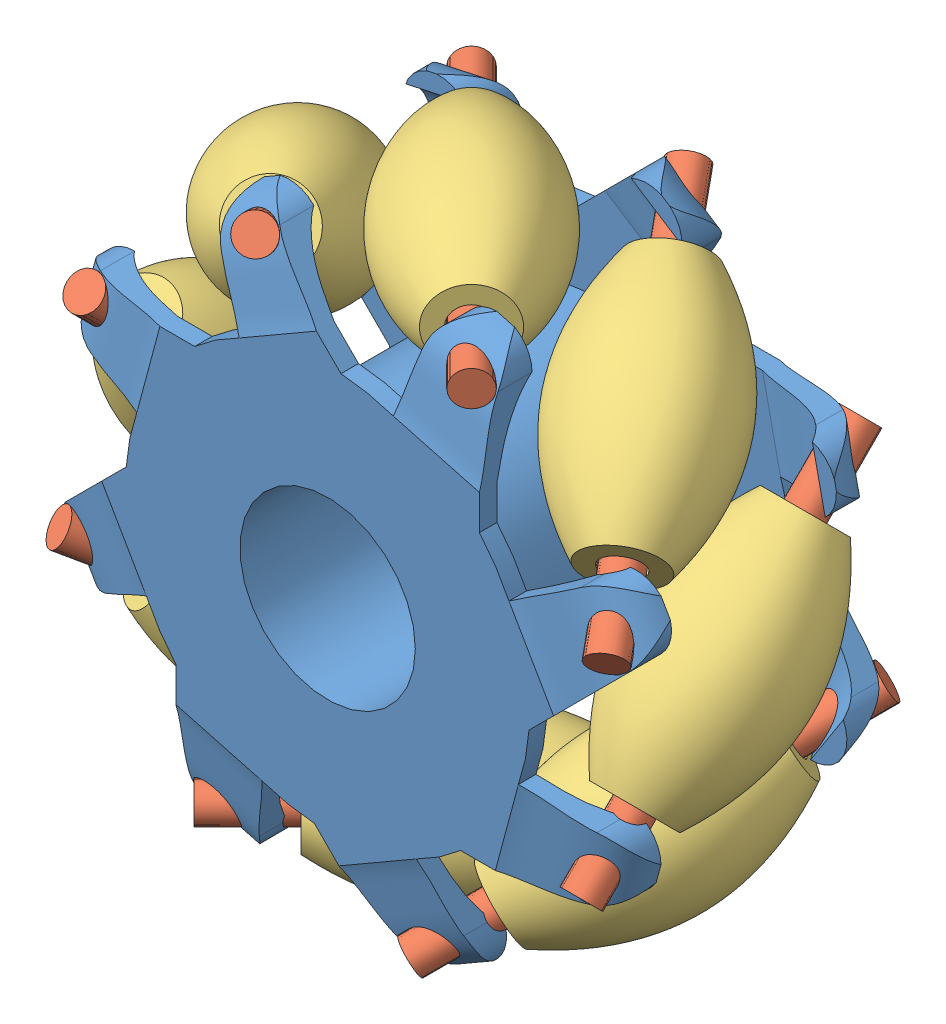
SolidWorks assembly Assem1, configuration Default. Lengths in mm.
Overall size (74.83 74.83 34.72).
17 component instances, 3 part files, 6 mates.
Components (placement in the parent):
- wheel_rim-1: wheel_rim [Default] at (28.8955 -22.2475 34.9813) size (66.41 66.41 33.64)
- wheel_rod-1: wheel_rod [Default] at (12.8892 6.0837 4.5688) x (0.707107 0 -0.707107) z (0.707107 0 0.707107) size (4 4 45)
- wheel_roller-1: wheel_roller [Default] at (28.9041 6.0837 20.5836) x (0 -1 0) z (-0.707107 0 0.707107) size (17.4 27.5 17.4)
- wheel_roller-9: wheel_roller [Default] at (8.8684 -2.2083 20.5836) x (0.707107 -0.707107 0) z (-0.5 -0.5 0.707107) size (17.4 27.5 17.4)
- wheel_roller-10: wheel_roller [Default] at (0.5643 -22.239 20.5836) x (1 0 0) z (0 -0.707107 0.707107) size (17.4 27.5 17.4)
- wheel_roller-11: wheel_roller [Default] at (8.8562 -42.2747 20.5836) x (0.707107 0.707107 0) z (0.5 -0.5 0.707107) size (17.4 27.5 17.4)
- wheel_roller-12: wheel_roller [Default] at (28.8869 -50.5788 20.5836) x (0 1 0) z (0.707107 0 0.707107) size (17.4 27.5 17.4)
- wheel_roller-13: wheel_roller [Default] at (48.9227 -42.2868 20.5836) x (-0.707107 0.707107 0) z (0.5 0.5 0.707107) size (17.4 27.5 17.4)
- wheel_roller-14: wheel_roller [Default] at (57.2268 -22.2561 20.5836) x (-1 0 0) z (0 0.707107 0.707107) size (17.4 27.5 17.4)
- wheel_roller-15: wheel_roller [Default] at (48.9348 -2.2204 20.5836) x (-0.707107 -0.707107 0) z (-0.5 0.5 0.707107) size (17.4 27.5 17.4)
- wheel_rod-9: wheel_rod [Default] at (-2.4558 -13.5325 4.5688) x (0.5 0.5 -0.707107) z (0.5 0.5 0.707107) size (4 4 45)
- wheel_rod-10: wheel_rod [Default] at (0.5643 -38.2538 4.5688) x (0 0.707107 -0.707107) z (0 0.707107 0.707107) size (4 4 45)
- wheel_rod-11: wheel_rod [Default] at (20.1805 -53.5989 4.5688) x (-0.5 0.5 -0.707107) z (-0.5 0.5 0.707107) size (4 4 45)
- wheel_rod-12: wheel_rod [Default] at (44.9018 -50.5788 4.5688) x (-0.707107 0 -0.707107) z (-0.707107 0 0.707107) size (4 4 45)
- wheel_rod-13: wheel_rod [Default] at (60.2469 -30.9626 4.5688) x (-0.5 -0.5 -0.707107) z (-0.5 -0.5 0.707107) size (4 4 45)
- wheel_rod-14: wheel_rod [Default] at (57.2268 -6.2413 4.5688) x (0 -0.707107 -0.707107) z (0 -0.707107 0.707107) size (4 4 45)
- wheel_rod-15: wheel_rod [Default] at (37.6106 9.1038 4.5688) x (0.5 -0.5 -0.707107) z (0.5 -0.5 0.707107) size (4 4 45)
Mates (geometry in assembly coordinates):
- Concentric1: concentric aligned: cylinder of wheel_rim-1 through (53.7009 6.0837 45.3804) axis (-0.707107 0 -0.707107) radius 2; cylinder of wheel_rod-1 through (44.709 6.0837 36.3886) axis (-0.707107 0 -0.707107) radius 2
- Concentric2: concentric anti-aligned: cylinder of wheel_rod-1 through (44.709 6.0837 36.3886) axis (-0.707107 0 -0.707107) radius 2; cylinder of wheel_roller-1 through (54.36 6.0837 46.0395) axis (0.707107 0 0.707107) radius 2.2
- Perpendicular1: perpendicular: plane of wheel_rod-1 through (12.8892 6.0837 4.5688) normal (0 1 0); plane of wheel_roller-1 through (28.9041 6.0837 20.5836) normal (0.707107 0 0.707107)
- Coincident3: coincident anti-aligned: plane of wheel_rod-1 through (12.8892 6.0837 4.5688) normal (0 1 0); plane of wheel_roller-1 through (28.9041 6.0837 20.5836) normal (0 -1 0)
- Lock1: lock: unknown of wheel_rim-1; unknown of wheel_rod-1
- Lock2: lock: unknown of wheel_rim-1; unknown of wheel_roller-1
